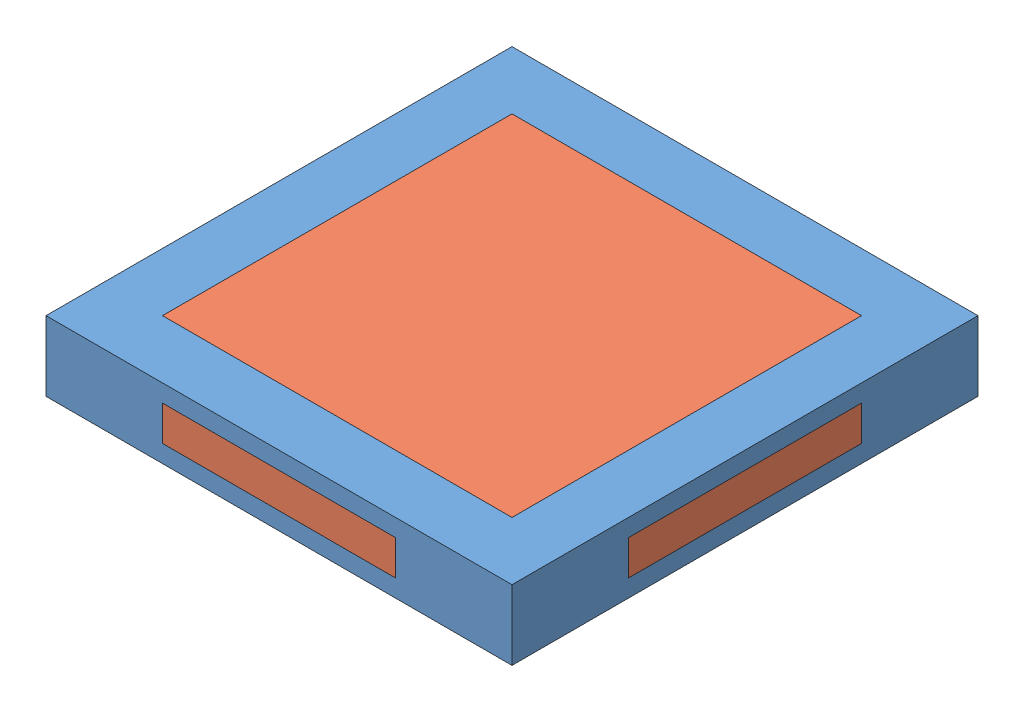
SolidWorks assembly Assem5, configuration Default. Lengths in mm.
Overall size (20 3 20).
2 component instances, 2 part files, 6 mates.
Components (placement in the parent):
- Square Outer-1: Square Outer [Default] at (4.2673 10.8454 15.9666) size (20 3 20)
- Square Inner-2: Square Inner [Default] at (4.2673 10.8454 15.9666) size (20 3 20)
Mates (geometry in assembly coordinates):
- Coincident1: coincident aligned: plane of Square Outer-1 through (14.2673 13.8454 25.9666) normal (1 0 0); plane of Square Inner-1 through (14.2673 13.0954 15.7429) normal (1 0 0)
- Coincident2: coincident anti-aligned: plane of Square Outer-1 through (14.2673 11.5954 20.9666) normal (0 1 0); plane of Square Inner-1 through (4.2673 11.5954 15.7429) normal (0 -1 0)
- Coincident3: coincident anti-aligned: plane of Square Outer-1 through (14.2673 11.5954 10.9666) normal (0 0 1); plane of Square Inner-1 through (4.2673 13.0954 10.7429) normal (0 0 -1)
- Coincident4: coincident: plane of Square Outer-1 through (11.7673 13.8454 23.4666) normal (-1 0 0); plane of Square Inner-2 through (11.7673 15.2941 15.9666) normal (1 0 0)
- Coincident7: coincident: plane of Square Outer-1 through (14.2673 13.8454 25.9666) normal (0 0 1); plane of Square Inner-2 through (4.2673 11.5954 25.9666) normal (0 0 1)
- Coincident8: coincident anti-aligned: plane of Square Outer-1 through (14.2673 11.5954 20.9666) normal (0 1 0); plane of Square Inner-2 through (4.2673 11.5954 15.9666) normal (0 -1 0)
